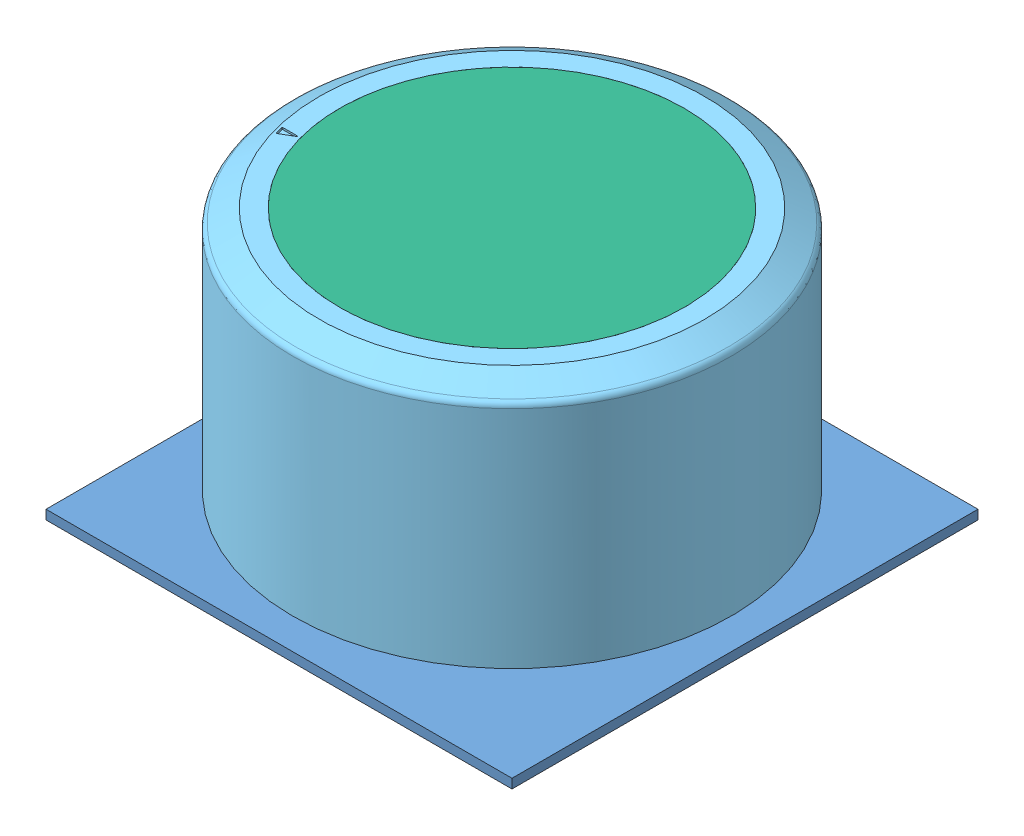
SolidWorks assembly 00-装配体 旋钮部分, configuration 默认. Lengths in mm.
Overall size (76.26 54.3 76.26).
10 component instances, 10 part files, 27 mates.
Components (placement in the parent):
- 01-零件 PCB板-1: 01-零件 PCB板 [默认] at origin size (50 1 50)
- 02-零件 电机底座-1: 02-零件 电机底座 [默认] at (0 6.2 0) size (46.19 23 52.91)
- 03-零件 电机-1: 03-零件 电机 [默认] at (0 4.58 0) x (0 0 1) z (-1 0 0) size (47.53 47.1 35.44)
- 04-零件 电机上罩-1: 04-零件 电机上罩 [默认] at (0 10.7 0) x (0.707107 0 0.707107) z (-0.707107 0 0.707107) size (56.5 12.14 51.36)
- 05-零件 旋钮上外壳-1: 05-零件 旋钮上外壳 [默认] at (0 2.8 0) x (0.965926 0 -0.258819) z (0.258819 0 0.965926) size (47 26.2 47)
- 06-零件 旋钮玻璃-1: 06-零件 旋钮玻璃 [默认] at (0 28 0) size (37 1 37)
- 07-零件 6x6x5轻触开关-1: 07-零件 6x6x5轻触开关 [默认] at (0 0 -10) x (-1 0 0) z (0 0 1) size (6 5 6)
- 零件 TFTLCD支撑圈-1: 零件 TFTLCD支撑圈 [默认] at (0 19 0) size (11.21 5.4 12)
- 零件 PCB-TFTLCD-1: 零件 PCB-TFTLCD [默认] at (0 24 0) x (1 0 0) z (0 1 0) size (38.77 35.97 1)
- 零件 TFT LCD 1.28inch-1: 零件 TFT LCD 1.28inch [默认] at (0 25.3 0) size (38.6 1.9 35.6)
Mates (geometry in assembly coordinates):
- 重合1: coincident anti-aligned: plane of 01-零件 PCB板-1 through (0 1 0) normal (0 1 0); plane of 02-零件 电机底座-1 through (-19 1 0) normal (0 -1 0)
- 平行1: parallel aligned: line of 01-零件 PCB板-1 through (25 1 25) axis (0 0 -1); line of 02-零件 电机底座-1 through (0 1 26.4551) axis (0 0 -1)
- 重合3: coincident: point of 01-零件 PCB板-1; point of 02-零件 电机底座-1
- 重合5: coincident anti-aligned: plane of 02-零件 电机底座-1 through (-17.5 6.2 0) normal (0 1 0); plane of 03-零件 电机-1 through (0 6.2 -6) normal (0 -1 0)
- 同心1: concentric aligned: circle of 02-零件 电机底座-1; circle of 03-零件 电机-1
- 同心2: concentric aligned: circle of 02-零件 电机底座-1; circle of 03-零件 电机-1
- 重合6: coincident anti-aligned: plane of 03-零件 电机-1 through (0 21.2 -17.25) normal (0 1 0); plane of 04-零件 电机上罩-1 through (-12.3744 21.2 -12.3744) normal (0 -1 0)
- 重合7: coincident anti-aligned: circle of 03-零件 电机-1; circle of 04-零件 电机上罩-1
- 同心3: concentric aligned: circle of 03-零件 电机-1; circle of 04-零件 电机上罩-1
- 重合8: coincident anti-aligned: plane of 04-零件 电机上罩-1 through (0 21.7 0) normal (0 1 0); plane of 05-零件 旋钮上外壳-1 through (-6.4152 21.7 21.0439) normal (0 -1 0)
- 同心4: concentric aligned: circle of 04-零件 电机上罩-1; circle of 05-零件 旋钮上外壳-1
- 平行2: parallel anti-aligned: line of 04-零件 电机上罩-1 through (20.6523 16.7 -6.1549) axis (-0.965926 0 0.258819); line of 05-零件 旋钮上外壳-1 through (19.1121 17 -5.8975) axis (0.965926 0 -0.258819)
- 重合10: coincident anti-aligned: plane of 05-零件 旋钮上外壳-1 through (-17.8696 28 4.7882) normal (0 1 0); plane of 06-零件 旋钮玻璃-1 through (0 28 0) normal (0 -1 0)
- 重合11: coincident anti-aligned: circle of 05-零件 旋钮上外壳-1; circle of 06-零件 旋钮玻璃-1
- 重合12: coincident anti-aligned: plane of 01-零件 PCB板-1 through (0 0 0) normal (0 -1 0); plane of 07-零件 6x6x5轻触开关-1 through (0 0 -10) normal (0 1 0)
- 平行3: parallel aligned: plane of 01-零件 PCB板-1 through (-25 1 -25) normal (0 0 -1); plane of 07-零件 6x6x5轻触开关-1 through (3 -3.5 -13) normal (0 0 -1)
- 对称1: symmetric aligned: plane of 01-零件 PCB板-1 through (0 0 0) normal (1 0 0); plane of 07-零件 6x6x5轻触开关-1 through (3 -3.5 -13) normal (1 0 0); plane of 07-零件 6x6x5轻触开关-1 through (-3 -3.5 -13) normal (-1 0 0)
- 距离2: distance = 12 mm aligned: plane of 07-零件 6x6x5轻触开关-1 through (3 -3.5 -13) normal (0 0 -1); plane of 01-零件 PCB板-1 through (-25 1 -25) normal (0 0 -1)
- 重合13: coincident anti-aligned: plane of 02-零件 电机底座-1 through (-3 19 0) normal (0 1 0); plane of 零件 TFTLCD支撑圈-1 through (-3 19 0) normal (0 -1 0)
- 同心5: concentric aligned: circle of 02-零件 电机底座-1; circle of 零件 TFTLCD支撑圈-1
- 重合14: coincident: line of 02-零件 电机底座-1 through (-2.958 19.8 -0.5) axis (0 -1 0); point of 零件 TFTLCD支撑圈-1
- 重合15: coincident anti-aligned: plane of 零件 TFTLCD支撑圈-1 through (-2.3 24 0) normal (0 1 0); plane of 零件 PCB-TFTLCD-1 through (0 24 0) normal (0 -1 0)
- 同心6: concentric anti-aligned: circle of 零件 TFTLCD支撑圈-1; circle of 零件 PCB-TFTLCD-1
- 平行4: parallel: line of 零件 TFTLCD支撑圈-1 through (-5.1933 24.4 2.99) axis (1 0 0); plane of 零件 PCB-TFTLCD-1 through (0 25 3) normal (0 0 -1)
- 重合18: coincident: plane of 零件 PCB-TFTLCD-1 through (0 25 0) normal (0 1 0); plane of 零件 TFT LCD 1.28inch-1 through (0 25 0) normal (0 -1 0)
- 同心7: concentric: circle of 零件 PCB-TFTLCD-1; circle of 零件 TFT LCD 1.28inch-1
- 平行5: parallel aligned: line of 零件 PCB-TFTLCD-1 through (20.7873 25 6.85) axis (0 0 -1); line of 零件 TFT LCD 1.28inch-1 through (20.3 26.8 6.75) axis (0 0 -1)
